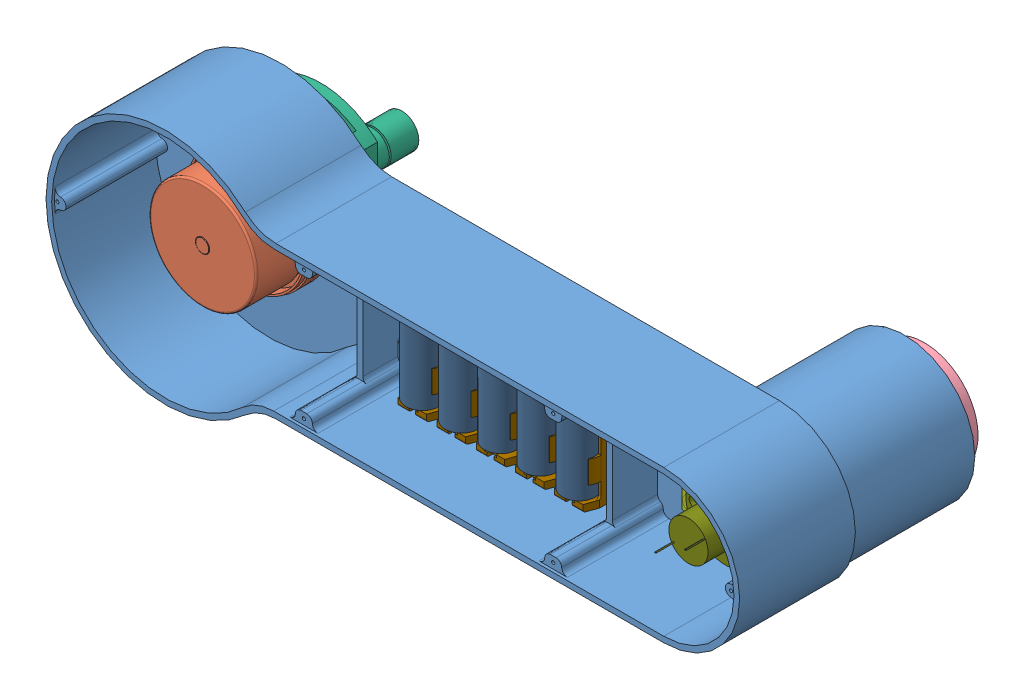
SolidWorks assembly Motor Link Assembly, configuration Default. Lengths in mm.
Overall size (388.62 133.35 146.05).
45 component instances, 16 part files, 61 mates.
Components (placement in the parent):
- Motor Link Frame-1: Motor Link Frame [Default] at (-32.059 -6.6158 -42.0522) size (388.62 133.35 134.94)
- EC60 Motor-1: EC60 Motor [Default] at (-32.059 -6.6158 -36.2772) x (0 0 1) z (-0.866025 0.5 0) size (61.3 68 68)
- Bearing - .750-1: Bearing - .750 [3760T241] at (247.341 -6.6158 -72.6122) x (-0.051747 0.99866 0) z (0 0 -1) size (41.27 41.27 11.11)
- Bearing - .750-2: Bearing - .750 [3760T241] at (247.341 -6.6158 -61.4997) x (0.885753 0.464157 0) z (0 0 -1) size (41.27 41.27 11.11)
- EM237 Magnet-1: EM237 Magnet [Default] at (247.341 -6.6158 -110.7589) x (0.987894 0.15513 0) z (-0.15513 0.987894 0) size (60.08 25.02 60.08)
- Magnet Holder Motor Link-1: Magnet Holder Motor Link [Default] at (249.9239 -3.5616 -98.2494) x (0.645723 0.763572 0) z (0.763572 -0.645723 0) size (50.8 73.42 50.6)
- Shaft_Carrier_Combined-1: Shaft_Carrier_Combined [Default] at (-32.059 -6.6158 -64.5147) x (0 -1 0) z (1 0 0) size (91.44 67.85 91.44)
- Magnet Encoders E3-X-750-X-H-D-X-1: Magnet Encoders E3-X-750-X-H-D-X [Default] at (247.341 -6.6158 -32.2732) x (-0.000397 -1 0) z (-1 0.000397 0) size (55.98 16.26 66.52)
- PCB_Battery Assembly-1: PCB_Battery Assembly [Default] at (208.1442 -28.2471 85.1479) x (1 0 0) z (0 1 0) size (127.38 21.9 77.22)
  - Battery PCB-1: Battery PCB [Default] at (-148.3186 115.135 -16.9005) x (1 0 0) z (0 -1 0) size (127.38 77.06 1.59)
  - Battery Assembly-1: Battery Assembly [Default] at (-101.6605 145.5711 -35.2548) x (-1 0 0) z (0 0 1) size (20.65 21.9 77.14)
    - Battery Holder - keystone-PN1043-1: Battery Holder - keystone-PN1043 [Default] at (27.979 42.1729 59.6018) size (20.65 18.93 77.14)
    - battery_6612-1: battery_6612 [Default] at (36.333 41.1675 88.8909) x (1 0 0) z (0 1 0) size (18.3 65.05 18.3)
  - Battery Assembly-2: Battery Assembly [Default] at (-130.4862 145.5711 78.5174) x (1 0 0) z (0 0 -1) size (20.65 21.9 77.14)
    - Battery Holder - keystone-PN1043-1: Battery Holder - keystone-PN1043 [Default] at (27.979 42.1729 59.6018) size (20.65 18.93 77.14)
    - battery_6612-1: battery_6612 [Default] at (36.333 41.1675 88.8909) x (1 0 0) z (0 1 0) size (18.3 65.05 18.3)
  - Battery Assembly-3: Battery Assembly [Default] at (-13.9797 145.5711 -35.2548) x (-1 0 0) z (0 0 1) size (20.65 21.9 77.14)
    - Battery Holder - keystone-PN1043-1: Battery Holder - keystone-PN1043 [Default] at (27.979 42.1729 59.6018) size (20.65 18.93 77.14)
    - battery_6612-1: battery_6612 [Default] at (36.333 41.1675 88.8909) x (1 0 0) z (0 1 0) size (18.3 65.05 18.3)
  - Battery Assembly-4: Battery Assembly [Default] at (-108.566 145.5711 78.5174) x (1 0 0) z (0 0 -1) size (20.65 21.9 77.14)
    - Battery Holder - keystone-PN1043-1: Battery Holder - keystone-PN1043 [Default] at (27.979 42.1729 59.6018) size (20.65 18.93 77.14)
    - battery_6612-1: battery_6612 [Default] at (36.333 41.1675 88.8909) x (1 0 0) z (0 1 0) size (18.3 65.05 18.3)
  - Battery Assembly-5: Battery Assembly [Default] at (-79.7403 145.5711 -35.2548) x (-1 0 0) z (0 0 1) size (20.65 21.9 77.14)
    - Battery Holder - keystone-PN1043-1: Battery Holder - keystone-PN1043 [Default] at (27.979 42.1729 59.6018) size (20.65 18.93 77.14)
    - battery_6612-1: battery_6612 [Default] at (36.333 41.1675 88.8909) x (1 0 0) z (0 1 0) size (18.3 65.05 18.3)
- 10-32 Button Cap Screw-1: 10-32 Button Cap Screw [92949A271] at (6.041 6.0842 -33.1368) x (-0.172399 -0.985027 0) z (0 0 1) size (9.17 9.17 28.15)
- 10-32 Thread Locking Nut-1: 10-32 Thread Locking Nut [90631A411] at (6.041 -19.3158 -48.4022) x (1 0 0) z (0 1 0) size (9.53 6.11 11)
- 10-32 Button Cap Screw-2: 10-32 Button Cap Screw [92949A271] at (-70.159 6.0842 -33.1368) x (-0.097934 0.995193 0) z (0 0 1) size (9.17 9.17 28.15)
- 10-32 Button Cap Screw-3: 10-32 Button Cap Screw [92949A271] at (-70.159 -19.3158 -33.1368) x (0.822451 -0.568836 0) z (0 0 1) size (9.17 9.17 28.15)
- 10-32 Button Cap Screw-4: 10-32 Button Cap Screw [92949A271] at (6.041 -19.3158 -33.1368) x (0.999756 0.022081 0) z (0 0 1) size (9.17 9.17 28.15)
- 10-32 Thread Locking Nut-2: 10-32 Thread Locking Nut [90631A411] at (6.041 6.0842 -48.4022) x (1 0 0) z (0 1 0) size (9.53 6.11 11)
- 10-32 Thread Locking Nut-3: 10-32 Thread Locking Nut [90631A411] at (-70.159 6.0842 -48.4022) x (1 0 0) z (0 1 0) size (9.53 6.11 11)
- 10-32 Thread Locking Nut-4: 10-32 Thread Locking Nut [90631A411] at (-70.159 -19.3158 -48.4022) x (1 0 0) z (0 1 0) size (9.53 6.11 11)
- 5-40 Bolt-1: 5-40 Bolt [91251A131] at (53.4755 -38.7976 -47.4497) x (-0.923728 -0.383049 0) z (0 0 -1) size (5.21 5.21 22.65)
- 5-40 Bolt-2: 5-40 Bolt [91251A131] at (53.4755 25.566 -47.4497) x (-0.923728 -0.383049 0) z (0 0 -1) size (5.21 5.21 22.65)
- 5-40 Bolt-3: 5-40 Bolt [91251A131] at (174.5065 -38.7976 -47.4497) x (-0.923728 -0.383049 0) z (0 0 -1) size (5.21 5.21 22.65)
- 5-40 Bolt-4: 5-40 Bolt [91251A131] at (174.5065 25.566 -47.4497) x (-0.923728 -0.383049 0) z (0 0 -1) size (5.21 5.21 22.65)
- 5-40 Nylon Locknut-1: 5-40 Nylon Locknut [90633A006] at (53.4755 -38.7976 -42.0522) x (1 0 0) z (0 1 0) size (6.35 2.87 7.33)
- 5-40 Nylon Locknut-2: 5-40 Nylon Locknut [90633A006] at (174.5065 -38.7976 -42.0522) x (1 0 0) z (0 1 0) size (6.35 2.87 7.33)
- 5-40 Nylon Locknut-3: 5-40 Nylon Locknut [90633A006] at (53.4755 25.566 -42.0522) x (1 0 0) z (0 1 0) size (6.35 2.87 7.33)
- 5-40 Nylon Locknut-4: 5-40 Nylon Locknut [90633A006] at (174.5065 25.566 -42.0522) x (1 0 0) z (0 1 0) size (6.35 2.87 7.33)
- M5 Nylon Spacer-1: M5 Nylon Spacer [93657A042] at (256.097 8.5361 -17.0812) x (0.923728 0.383049 0) z (0 0 -1) size (8 8 6)
- M5 Nylon Spacer-2: M5 Nylon Spacer [93657A042] at (229.841 -6.6089 -17.0812) x (0.923728 0.383049 0) z (0 0 -1) size (8 8 6)
- M5 Nylon Spacer-3: M5 Nylon Spacer [93657A042] at (256.085 -21.7748 -17.0812) x (0.923728 0.383049 0) z (0 0 -1) size (8 8 6)
- Slip Ring M322M1-0202-1: Slip Ring M322M1-0202 [Default] at (247.341 -6.6158 -11.6812) x (-0.866224 -0.499656 0) z (0 0 -1) size (44 44 57)
Mates (geometry in assembly coordinates):
- Concentric1: concentric aligned: cylinder of Motor Link Frame-1 through (-32.059 -6.6158 -55.5225) axis (0 0 1) radius 4.7625; line of EC60 Motor-1 through (-32.059 -6.6158 -57.9092) axis (0 0 1)
- Coincident1: coincident anti-aligned: plane of Motor Link Frame-1 through (-32.059 -6.6158 -38.8772) normal (0 0 1); plane of EC60 Motor-1 through (-26.559 2.9104 -38.8772) normal (0 0 -1)
- Concentric2: concentric aligned: cylinder of Motor Link Frame-1 through (-21.309 12.0037 -42.0522) axis (0 0 -1) radius 2.25; cylinder of EC60 Motor-1 through (-21.309 12.0037 -36.2772) axis (0 0 -1) radius 1.65
- Concentric3: concentric anti-aligned: line of Motor Link Frame-1 through (247.341 -6.6158 -112.1562) axis (0 0 1); cylinder of Bearing - .750-1 through (247.341 -6.6158 -78.1684) axis (0 0 -1) radius 9.525
- Coincident3: coincident anti-aligned: plane of Motor Link Frame-1 through (267.9785 -6.6158 -78.1684) normal (0 0 1); plane of Bearing - .750-1 through (267.396 -5.5767 -78.1684) normal (0 0 -1)
- Concentric4: concentric anti-aligned: line of Motor Link Frame-1 through (247.341 -6.6158 -112.1562) axis (0 0 1); cylinder of Bearing - .750-2 through (247.341 -6.6158 -67.0559) axis (0 0 -1) radius 9.525
- Coincident6: coincident anti-aligned: plane of Bearing - .750-1 through (257.4081 -6.0942 -67.0559) normal (0 0 1); plane of Bearing - .750-2 through (253.7257 -18.7998 -67.0559) normal (0 0 -1)
- Concentric6: concentric anti-aligned: line of Motor Link Frame-1 through (247.341 -6.6158 -112.1562) axis (0 0 1); cylinder of Magnet Holder Motor Link-1 through (247.341 -6.6158 -98.2494) axis (0 0 -1) radius 9.525
- Coincident7: coincident anti-aligned: plane of Bearing - .750-1 through (261.078 -5.904 -78.1684) normal (0 0 -1); plane of Magnet Holder Motor Link-1 through (255.5417 3.0815 -78.1684) normal (0 0 1)
- Concentric7: concentric aligned: line of Motor Link Frame-1 through (247.341 -6.6158 -112.1562) axis (0 0 1); cylinder of EM237 Magnet-1 through (247.341 -6.6158 -98.2494) axis (0 0 1) radius 3.4036
- Coincident8: coincident anti-aligned: plane of EM237 Magnet-1 through (247.341 -6.6158 -98.2494) normal (0 0 1); plane of Magnet Holder Motor Link-1 through (249.9239 -3.5616 -98.2494) normal (0 0 -1)
- Concentric8: concentric aligned: cylinder of EC60 Motor-1 through (-32.059 -6.6158 -59.3772) axis (0 0 1) radius 4; line of Shaft_Carrier_Combined-1 through (-32.059 -6.6158 -109.9045) axis (0 0 1)
- Coincident9: coincident aligned: line of Motor Link Frame-1 through (-32.059 21.3842 -42.0522) axis (0 0 1); line of Shaft_Carrier_Combined-1 through (-32.059 21.3842 -63.9272) axis (0 0 1)
- Coincident10: coincident anti-aligned: plane of Motor Link Frame-1 through (-32.059 -6.6158 -42.0522) normal (0 0 -1); plane of Shaft_Carrier_Combined-1 through (-32.059 -6.6158 -42.0522) normal (0 0 1)
- Concentric9: concentric aligned: line of Motor Link Frame-1 through (247.341 -6.6158 -112.1562) axis (0 0 1); cylinder of Magnet Encoders E3-X-750-X-H-D-X-1 through (247.341 -6.6158 -25.72) axis (0 0 1) radius 9.5263
- Coincident11: coincident anti-aligned: plane of Motor Link Frame-1 through (247.341 -6.6158 -35.7022) normal (0 0 1); plane of Magnet Encoders E3-X-750-X-H-D-X-1 through (247.341 -6.6158 -35.7022) normal (0 0 -1)
- Concentric10: concentric aligned: cylinder of PCB_Battery Assembly-1/Battery PCB-1 through (53.4755 25.566 -28.3997) axis (0 0 -1) radius 1.651; cylinder of Motor Link Frame-1 through (53.4755 25.566 -29.9872) axis (0 0 -1) radius 1.651
- Concentric11: concentric aligned: cylinder of PCB_Battery Assembly-1/Battery PCB-1 through (174.5065 25.566 -28.3997) axis (0 0 -1) radius 1.651; cylinder of Motor Link Frame-1 through (174.5065 25.566 -29.9872) axis (0 0 -1) radius 1.651
- Coincident12: coincident anti-aligned: plane of Motor Link Frame-1 through (-32.059 -6.6158 -29.9872) normal (0 0 1); plane of PCB_Battery Assembly-1/Battery PCB-1 through (59.8255 -45.1476 -29.9872) normal (0 0 -1)
- Concentric12: concentric anti-aligned: cylinder of Shaft_Carrier_Combined-1 through (6.041 6.0842 -71.2498) axis (0 0 1) radius 2.3813; cylinder of 10-32 Button Cap Screw-1 through (6.041 6.0842 -61.1022) axis (0 0 -1) radius 2.413
- Concentric13: concentric anti-aligned: cylinder of Shaft_Carrier_Combined-1 through (-70.159 6.0842 -71.2498) axis (0 0 1) radius 2.3813; cylinder of 10-32 Button Cap Screw-2 through (-70.159 6.0842 -61.1022) axis (0 0 -1) radius 2.413
- Concentric14: concentric anti-aligned: cylinder of Shaft_Carrier_Combined-1 through (-70.159 -19.3158 -71.2498) axis (0 0 1) radius 2.3813; cylinder of 10-32 Button Cap Screw-3 through (-70.159 -19.3158 -61.1022) axis (0 0 -1) radius 2.413
- Concentric15: concentric anti-aligned: cylinder of Shaft_Carrier_Combined-1 through (6.041 -19.3158 -71.2498) axis (0 0 1) radius 2.3813; cylinder of 10-32 Button Cap Screw-4 through (6.041 -19.3158 -61.1022) axis (0 0 -1) radius 2.413
- Coincident13: coincident anti-aligned: plane of Motor Link Frame-1 through (247.341 -6.6158 -35.7022) normal (0 0 1); plane of 10-32 Button Cap Screw-1 through (1.525 6.8746 -35.7022) normal (0 0 -1)
- Coincident14: coincident anti-aligned: plane of Motor Link Frame-1 through (247.341 -6.6158 -35.7022) normal (0 0 1); plane of 10-32 Button Cap Screw-4 through (6.1423 -23.8994 -35.7022) normal (0 0 -1)
- Coincident15: coincident anti-aligned: plane of Motor Link Frame-1 through (247.341 -6.6158 -35.7022) normal (0 0 1); plane of 10-32 Button Cap Screw-3 through (-72.7669 -23.0865 -35.7022) normal (0 0 -1)
- Coincident16: coincident anti-aligned: plane of Motor Link Frame-1 through (247.341 -6.6158 -35.7022) normal (0 0 1); plane of 10-32 Button Cap Screw-2 through (-65.5963 6.5332 -35.7022) normal (0 0 -1)
- Concentric16: concentric anti-aligned: circle of 10-32 Thread Locking Nut-1; cylinder of 10-32 Button Cap Screw-4 through (6.041 -19.3158 -61.1022) axis (0 0 -1) radius 2.413
- Concentric17: concentric anti-aligned: cylinder of 10-32 Button Cap Screw-3 through (-70.159 -19.3158 -61.1022) axis (0 0 -1) radius 2.413; circle of 10-32 Thread Locking Nut-4
- Concentric18: concentric anti-aligned: cylinder of 10-32 Button Cap Screw-2 through (-70.159 6.0842 -61.1022) axis (0 0 -1) radius 2.413; circle of 10-32 Thread Locking Nut-3
- Concentric19: concentric anti-aligned: circle of 10-32 Thread Locking Nut-2; cylinder of 10-32 Button Cap Screw-1 through (6.041 6.0842 -61.1022) axis (0 0 -1) radius 2.413
- Coincident17: coincident anti-aligned: plane of Shaft_Carrier_Combined-1 through (-32.059 -6.6158 -48.4022) normal (0 0 -1); plane of 10-32 Thread Locking Nut-1 through (6.041 -24.8151 -48.4022) normal (0 0 1)
- Coincident18: coincident anti-aligned: plane of Shaft_Carrier_Combined-1 through (-32.059 -6.6158 -48.4022) normal (0 0 -1); plane of 10-32 Thread Locking Nut-2 through (6.041 0.5849 -48.4022) normal (0 0 1)
- Coincident19: coincident anti-aligned: plane of Shaft_Carrier_Combined-1 through (-32.059 -6.6158 -48.4022) normal (0 0 -1); plane of 10-32 Thread Locking Nut-3 through (-70.159 0.5849 -48.4022) normal (0 0 1)
- Coincident20: coincident anti-aligned: plane of Shaft_Carrier_Combined-1 through (-32.059 -6.6158 -48.4022) normal (0 0 -1); plane of 10-32 Thread Locking Nut-4 through (-70.159 -24.8151 -48.4022) normal (0 0 1)
- Concentric20: concentric aligned: cylinder of Motor Link Frame-1 through (53.4755 25.566 -29.9872) axis (0 0 -1) radius 1.651; cylinder of 5-40 Bolt-2 through (53.4755 25.566 -25.2247) axis (0 0 -1) radius 2.6035
- Concentric21: concentric aligned: cylinder of Motor Link Frame-1 through (53.4755 -38.7976 -29.9872) axis (0 0 -1) radius 1.651; cylinder of 5-40 Bolt-1 through (53.4755 -38.7976 -25.2247) axis (0 0 -1) radius 2.6035
- Concentric22: concentric aligned: cylinder of Motor Link Frame-1 through (174.5065 -38.7976 -29.9872) axis (0 0 -1) radius 1.651; cylinder of 5-40 Bolt-3 through (174.5065 -38.7976 -25.2247) axis (0 0 -1) radius 2.6035
- Concentric23: concentric aligned: cylinder of Motor Link Frame-1 through (174.5065 25.566 -29.9872) axis (0 0 -1) radius 1.651; cylinder of 5-40 Bolt-4 through (174.5065 25.566 -25.2247) axis (0 0 -1) radius 2.6035
- Coincident21: coincident anti-aligned: plane of PCB_Battery Assembly-1/Battery PCB-1 through (59.8255 -45.1476 -28.3997) normal (0 0 1); plane of 5-40 Bolt-2 through (53.4755 25.566 -28.3997) normal (0 0 -1)
- Coincident22: coincident anti-aligned: plane of PCB_Battery Assembly-1/Battery PCB-1 through (59.8255 -45.1476 -28.3997) normal (0 0 1); plane of 5-40 Bolt-1 through (53.4755 -38.7976 -28.3997) normal (0 0 -1)
- Concentric24: concentric anti-aligned: circle of Motor Link Frame-1; circle of 5-40 Nylon Locknut-1
- Coincident23: coincident anti-aligned: plane of Motor Link Frame-1 through (-32.059 -6.6158 -42.0522) normal (0 0 -1); plane of 5-40 Nylon Locknut-1 through (50.3005 -44.2969 -42.0522) normal (0 0 1)
- Coincident24: coincident anti-aligned: plane of PCB_Battery Assembly-1/Battery PCB-1 through (59.8255 -45.1476 -28.3997) normal (0 0 1); plane of 5-40 Bolt-4 through (174.5065 25.566 -28.3997) normal (0 0 -1)
- Coincident25: coincident anti-aligned: plane of PCB_Battery Assembly-1/Battery PCB-1 through (59.8255 -45.1476 -28.3997) normal (0 0 1); plane of 5-40 Bolt-3 through (174.5065 -38.7976 -28.3997) normal (0 0 -1)
- Concentric25: concentric anti-aligned: cylinder of 5-40 Bolt-2 through (53.4755 25.566 -25.2247) axis (0 0 -1) radius 2.6035; circle of 5-40 Nylon Locknut-3
- Coincident26: coincident anti-aligned: plane of Motor Link Frame-1 through (-32.059 -6.6158 -42.0522) normal (0 0 -1); plane of 5-40 Nylon Locknut-3 through (50.3005 20.0667 -42.0522) normal (0 0 1)
- Concentric26: concentric anti-aligned: circle of 5-40 Bolt-4; circle of 5-40 Nylon Locknut-4
- Coincident27: coincident anti-aligned: plane of Motor Link Frame-1 through (-32.059 -6.6158 -42.0522) normal (0 0 -1); plane of 5-40 Nylon Locknut-4 through (171.3315 20.0667 -42.0522) normal (0 0 1)
- Concentric27: concentric anti-aligned: cylinder of 5-40 Bolt-3 through (174.5065 -38.7976 -25.2247) axis (0 0 -1) radius 2.6035; circle of 5-40 Nylon Locknut-2
- Coincident28: coincident anti-aligned: plane of Motor Link Frame-1 through (-32.059 -6.6158 -42.0522) normal (0 0 -1); plane of 5-40 Nylon Locknut-2 through (171.3315 -44.2969 -42.0522) normal (0 0 1)
- Concentric28: concentric aligned: cylinder of Magnet Encoders E3-X-750-X-H-D-X-1 through (229.841 -6.6089 -20.0812) axis (0 0 1) radius 2.1; cylinder of M5 Nylon Spacer-2 through (229.841 -6.6089 -20.0812) axis (0 0 1) radius 2.65
- Concentric29: concentric aligned: cylinder of Magnet Encoders E3-X-750-X-H-D-X-1 through (256.085 -21.7748 -20.0812) axis (0 0 1) radius 2.1; cylinder of M5 Nylon Spacer-3 through (256.085 -21.7748 -20.0812) axis (0 0 1) radius 2.65
- Concentric30: concentric aligned: cylinder of Magnet Encoders E3-X-750-X-H-D-X-1 through (256.097 8.5361 -20.0812) axis (0 0 1) radius 2.1; cylinder of M5 Nylon Spacer-1 through (256.097 8.5361 -20.0812) axis (0 0 1) radius 2.65
- Coincident29: coincident anti-aligned: plane of Magnet Encoders E3-X-750-X-H-D-X-1 through (247.341 -6.6158 -20.0812) normal (0 0 1); plane of M5 Nylon Spacer-1 through (256.097 8.5361 -20.0812) normal (0 0 -1)
- Coincident30: coincident anti-aligned: plane of Magnet Encoders E3-X-750-X-H-D-X-1 through (247.341 -6.6158 -20.0812) normal (0 0 1); plane of M5 Nylon Spacer-2 through (229.841 -6.6089 -20.0812) normal (0 0 -1)
- Coincident31: coincident anti-aligned: plane of Magnet Encoders E3-X-750-X-H-D-X-1 through (247.341 -6.6158 -20.0812) normal (0 0 1); plane of M5 Nylon Spacer-3 through (256.085 -21.7748 -20.0812) normal (0 0 -1)
- Concentric33: concentric aligned: cylinder of Slip Ring M322M1-0202-1 through (247.341 -6.6158 -19.0812) axis (0 0 1) radius 11; line of Motor Link Frame-1 through (247.341 -6.6158 -112.1562) axis (0 0 1)
- Parallel1: parallel: line of Motor Link Frame-1 through (-32.059 -6.6158 -38.8772) axis (0.999935 0 0.011363); plane of Magnet Encoders E3-X-750-X-H-D-X-1 through (221.6012 -27.1288 -33.848) normal (-0.000397 -0.999391 0.034899)
- Concentric35: concentric aligned: cylinder of M5 Nylon Spacer-2 through (229.841 -6.6089 -20.0812) axis (0 0 1) radius 2.65; cylinder of Slip Ring M322M1-0202-1 through (229.841 -6.6089 -11.6812) axis (0 0 1) radius 2.75
- Coincident34: coincident anti-aligned: plane of M5 Nylon Spacer-3 through (256.085 -21.7748 -14.0812) normal (0 0 1); plane of Slip Ring M322M1-0202-1 through (228.2841 -17.6083 -14.0812) normal (0 0 -1)
